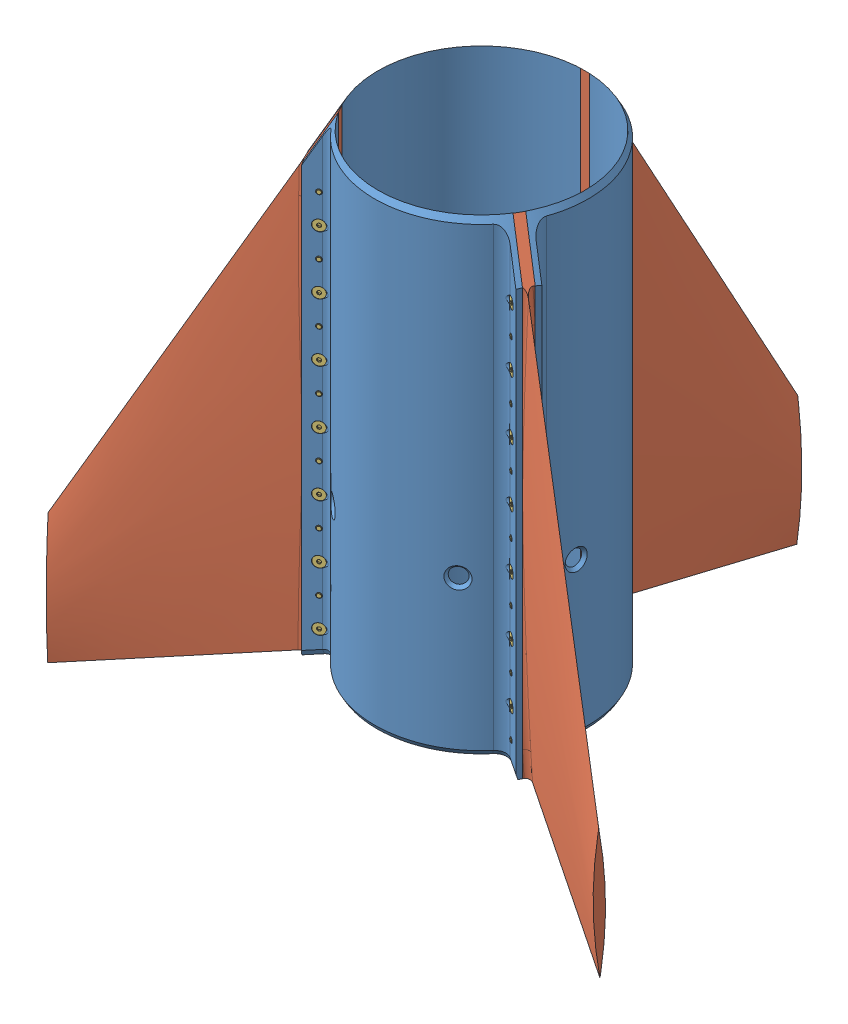
SolidWorks assembly Fin Can 3 Fin Asm, configuration Default. Lengths in mm.
Overall size (544.77 508.03 473.71).
50 component instances, 4 part files, 17 mates.
Components (placement in the parent):
- Binder Fin Can Section 3 - countersink 1-1: Binder Fin Can Section 3 - countersink 1 [Default] at origin size (110.04 463.46 186.39)
- BiconvexFin 3 Fin Fillet-4: BiconvexFin 3 Fin Fillet [Default] at (85.524 466.7433 54.8623) x (0 -1 0) z (0.866025 0 0.5) size (507.85 12.04 209.48)
- 91253A008_ 10-32 Black-Oxide Alloy Steel Hex Drive Flat Head Screw-1: 91253A008_ 10-32 Black-Oxide Alloy Steel Hex Drive Flat Head Screw [91253A008] at (0.3377 28.5749 -114.1971) x (0 0 1) z (-1 0 0) size (10.44 10.44 19.55)
- 91253A008_ 10-32 Black-Oxide Alloy Steel Hex Drive Flat Head Screw-28: 91253A008_ 10-32 Black-Oxide Alloy Steel Hex Drive Flat Head Screw [91253A008] at (-0.3377 57.15 -114.1971) x (0 0 1) z (1 0 0) size (10.44 10.44 19.55)
- 91253A008_ 10-32 Black-Oxide Alloy Steel Hex Drive Flat Head Screw-35: 91253A008_ 10-32 Black-Oxide Alloy Steel Hex Drive Flat Head Screw [91253A008] at (98.7287 28.5749 57.391) x (-0.866025 0 -0.5) z (0.5 0 -0.866025) size (10.44 10.44 19.55)
- 91253A008_ 10-32 Black-Oxide Alloy Steel Hex Drive Flat Head Screw-42: 91253A008_ 10-32 Black-Oxide Alloy Steel Hex Drive Flat Head Screw [91253A008] at (99.0664 57.15 56.8061) x (-0.801823 -0.377852 -0.462933) z (-0.5 0 0.866025) size (10.44 10.44 19.55)
- 91253A008_ 10-32 Black-Oxide Alloy Steel Hex Drive Flat Head Screw-49: 91253A008_ 10-32 Black-Oxide Alloy Steel Hex Drive Flat Head Screw [91253A008] at (-99.0664 28.5749 56.8061) x (-0.801823 -0.377852 0.462933) z (0.5 0 0.866025) size (10.44 10.44 19.55)
- 91253A008_ 10-32 Black-Oxide Alloy Steel Hex Drive Flat Head Screw-56: 91253A008_ 10-32 Black-Oxide Alloy Steel Hex Drive Flat Head Screw [91253A008] at (-98.7287 57.15 57.391) x (-0.801823 0.377852 0.462933) z (-0.5 0 -0.866025) size (10.44 10.44 19.55)
- Top Covers-2: Top Covers [Default] at (-230.5618 44.8886 -221.6505) x (0.414372 0.876196 -0.246124) z (0.563549 -0.034671 0.825355) (suppressed, hidden)
- Fin Bottom Wood-1: Fin Bottom Wood [Default] at (-200.4343 -0.6568 97.2389) x (0.854065 0.257277 -0.452086) z (0.461539 0.026031 0.886738) (suppressed, hidden)
- BiconvexFin 3 Fin Fillet-5: BiconvexFin 3 Fin Fillet [Default] at (4.7501 466.7433 -101.4971) x (0 -1 0) z (0 0 -1) size (507.85 12.04 209.48)
- BiconvexFin 3 Fin Fillet-6: BiconvexFin 3 Fin Fillet [Default] at (-90.2741 466.7433 46.6348) x (0 -1 0) z (-0.866025 0 0.5) size (507.85 12.04 209.48)
- Binder Fin Can Section 3 - countersink 1-2: Binder Fin Can Section 3 - countersink 1 [Default] x (-0.5 0 -0.866025) z (0.866025 0 -0.5) size (110.04 463.46 186.39)
- Binder Fin Can Section 3 - countersink 1-3: Binder Fin Can Section 3 - countersink 1 [Default] x (-0.5 0 0.866025) z (-0.866025 0 -0.5) size (110.04 463.46 186.39)
- 91253A008_ 10-32 Black-Oxide Alloy Steel Hex Drive Flat Head Screw-2: 91253A008_ 10-32 Black-Oxide Alloy Steel Hex Drive Flat Head Screw [91253A008] at (0.3377 85.7249 -114.1971) x (0 0 1) z (-1 0 0) size (10.44 10.44 19.55)
- 91253A008_ 10-32 Black-Oxide Alloy Steel Hex Drive Flat Head Screw-3: 91253A008_ 10-32 Black-Oxide Alloy Steel Hex Drive Flat Head Screw [91253A008] at (0.3377 142.8749 -114.1971) x (0 0 1) z (-1 0 0) size (10.44 10.44 19.55)
- 91253A008_ 10-32 Black-Oxide Alloy Steel Hex Drive Flat Head Screw-4: 91253A008_ 10-32 Black-Oxide Alloy Steel Hex Drive Flat Head Screw [91253A008] at (0.3377 200.0249 -114.1971) x (0 0 1) z (-1 0 0) size (10.44 10.44 19.55)
- 91253A008_ 10-32 Black-Oxide Alloy Steel Hex Drive Flat Head Screw-25: 91253A008_ 10-32 Black-Oxide Alloy Steel Hex Drive Flat Head Screw [91253A008] at (0.3377 257.1749 -114.1971) x (0 0 1) z (-1 0 0) size (10.44 10.44 19.55)
- 91253A008_ 10-32 Black-Oxide Alloy Steel Hex Drive Flat Head Screw-26: 91253A008_ 10-32 Black-Oxide Alloy Steel Hex Drive Flat Head Screw [91253A008] at (0.3377 314.3249 -114.1971) x (0 0 1) z (-1 0 0) size (10.44 10.44 19.55)
- 91253A008_ 10-32 Black-Oxide Alloy Steel Hex Drive Flat Head Screw-27: 91253A008_ 10-32 Black-Oxide Alloy Steel Hex Drive Flat Head Screw [91253A008] at (0.3377 371.4749 -114.1971) x (0 0 1) z (-1 0 0) size (10.44 10.44 19.55)
- 91253A008_ 10-32 Black-Oxide Alloy Steel Hex Drive Flat Head Screw-29: 91253A008_ 10-32 Black-Oxide Alloy Steel Hex Drive Flat Head Screw [91253A008] at (-0.3377 114.3 -114.1971) x (0 0 1) z (1 0 0) size (10.44 10.44 19.55)
- 91253A008_ 10-32 Black-Oxide Alloy Steel Hex Drive Flat Head Screw-30: 91253A008_ 10-32 Black-Oxide Alloy Steel Hex Drive Flat Head Screw [91253A008] at (-0.3377 171.45 -114.1971) x (0 0 1) z (1 0 0) size (10.44 10.44 19.55)
- 91253A008_ 10-32 Black-Oxide Alloy Steel Hex Drive Flat Head Screw-31: 91253A008_ 10-32 Black-Oxide Alloy Steel Hex Drive Flat Head Screw [91253A008] at (-0.3377 228.6 -114.1971) x (0 0 1) z (1 0 0) size (10.44 10.44 19.55)
- 91253A008_ 10-32 Black-Oxide Alloy Steel Hex Drive Flat Head Screw-32: 91253A008_ 10-32 Black-Oxide Alloy Steel Hex Drive Flat Head Screw [91253A008] at (-0.3377 285.75 -114.1971) x (0 0 1) z (1 0 0) size (10.44 10.44 19.55)
- 91253A008_ 10-32 Black-Oxide Alloy Steel Hex Drive Flat Head Screw-33: 91253A008_ 10-32 Black-Oxide Alloy Steel Hex Drive Flat Head Screw [91253A008] at (-0.3377 342.9 -114.1971) x (0 0 1) z (1 0 0) size (10.44 10.44 19.55)
- 91253A008_ 10-32 Black-Oxide Alloy Steel Hex Drive Flat Head Screw-34: 91253A008_ 10-32 Black-Oxide Alloy Steel Hex Drive Flat Head Screw [91253A008] at (-0.3377 400.05 -114.1971) x (0 0 1) z (1 0 0) size (10.44 10.44 19.55)
- 91253A008_ 10-32 Black-Oxide Alloy Steel Hex Drive Flat Head Screw-36: 91253A008_ 10-32 Black-Oxide Alloy Steel Hex Drive Flat Head Screw [91253A008] at (98.7287 85.7249 57.391) x (-0.866025 0 -0.5) z (0.5 0 -0.866025) size (10.44 10.44 19.55)
- 91253A008_ 10-32 Black-Oxide Alloy Steel Hex Drive Flat Head Screw-37: 91253A008_ 10-32 Black-Oxide Alloy Steel Hex Drive Flat Head Screw [91253A008] at (98.7287 142.8749 57.391) x (-0.866025 0 -0.5) z (0.5 0 -0.866025) size (10.44 10.44 19.55)
- 91253A008_ 10-32 Black-Oxide Alloy Steel Hex Drive Flat Head Screw-38: 91253A008_ 10-32 Black-Oxide Alloy Steel Hex Drive Flat Head Screw [91253A008] at (98.7287 200.0249 57.391) x (-0.866025 0 -0.5) z (0.5 0 -0.866025) size (10.44 10.44 19.55)
- 91253A008_ 10-32 Black-Oxide Alloy Steel Hex Drive Flat Head Screw-39: 91253A008_ 10-32 Black-Oxide Alloy Steel Hex Drive Flat Head Screw [91253A008] at (98.7287 257.1749 57.391) x (-0.866025 0 -0.5) z (0.5 0 -0.866025) size (10.44 10.44 19.55)
- 91253A008_ 10-32 Black-Oxide Alloy Steel Hex Drive Flat Head Screw-40: 91253A008_ 10-32 Black-Oxide Alloy Steel Hex Drive Flat Head Screw [91253A008] at (98.7287 314.3249 57.391) x (-0.866025 0 -0.5) z (0.5 0 -0.866025) size (10.44 10.44 19.55)
- 91253A008_ 10-32 Black-Oxide Alloy Steel Hex Drive Flat Head Screw-41: 91253A008_ 10-32 Black-Oxide Alloy Steel Hex Drive Flat Head Screw [91253A008] at (98.7287 371.4749 57.391) x (-0.866025 0 -0.5) z (0.5 0 -0.866025) size (10.44 10.44 19.55)
- 91253A008_ 10-32 Black-Oxide Alloy Steel Hex Drive Flat Head Screw-43: 91253A008_ 10-32 Black-Oxide Alloy Steel Hex Drive Flat Head Screw [91253A008] at (99.0664 114.3 56.8061) x (-0.801823 -0.377852 -0.462933) z (-0.5 0 0.866025) size (10.44 10.44 19.55)
- 91253A008_ 10-32 Black-Oxide Alloy Steel Hex Drive Flat Head Screw-44: 91253A008_ 10-32 Black-Oxide Alloy Steel Hex Drive Flat Head Screw [91253A008] at (99.0664 171.45 56.8061) x (-0.801823 -0.377852 -0.462933) z (-0.5 0 0.866025) size (10.44 10.44 19.55)
- 91253A008_ 10-32 Black-Oxide Alloy Steel Hex Drive Flat Head Screw-45: 91253A008_ 10-32 Black-Oxide Alloy Steel Hex Drive Flat Head Screw [91253A008] at (99.0664 228.6 56.8061) x (-0.801823 -0.377852 -0.462933) z (-0.5 0 0.866025) size (10.44 10.44 19.55)
- 91253A008_ 10-32 Black-Oxide Alloy Steel Hex Drive Flat Head Screw-46: 91253A008_ 10-32 Black-Oxide Alloy Steel Hex Drive Flat Head Screw [91253A008] at (99.0664 285.75 56.8061) x (-0.801823 -0.377852 -0.462933) z (-0.5 0 0.866025) size (10.44 10.44 19.55)
- 91253A008_ 10-32 Black-Oxide Alloy Steel Hex Drive Flat Head Screw-47: 91253A008_ 10-32 Black-Oxide Alloy Steel Hex Drive Flat Head Screw [91253A008] at (99.0664 342.9 56.8061) x (-0.801823 -0.377852 -0.462933) z (-0.5 0 0.866025) size (10.44 10.44 19.55)
- 91253A008_ 10-32 Black-Oxide Alloy Steel Hex Drive Flat Head Screw-48: 91253A008_ 10-32 Black-Oxide Alloy Steel Hex Drive Flat Head Screw [91253A008] at (99.0664 400.05 56.8061) x (-0.801823 -0.377852 -0.462933) z (-0.5 0 0.866025) size (10.44 10.44 19.55)
- 91253A008_ 10-32 Black-Oxide Alloy Steel Hex Drive Flat Head Screw-50: 91253A008_ 10-32 Black-Oxide Alloy Steel Hex Drive Flat Head Screw [91253A008] at (-99.0664 85.7249 56.8061) x (-0.801823 -0.377852 0.462933) z (0.5 0 0.866025) size (10.44 10.44 19.55)
- 91253A008_ 10-32 Black-Oxide Alloy Steel Hex Drive Flat Head Screw-51: 91253A008_ 10-32 Black-Oxide Alloy Steel Hex Drive Flat Head Screw [91253A008] at (-99.0664 142.8749 56.8061) x (-0.801823 -0.377852 0.462933) z (0.5 0 0.866025) size (10.44 10.44 19.55)
- 91253A008_ 10-32 Black-Oxide Alloy Steel Hex Drive Flat Head Screw-52: 91253A008_ 10-32 Black-Oxide Alloy Steel Hex Drive Flat Head Screw [91253A008] at (-99.0664 200.0249 56.8061) x (-0.801823 -0.377852 0.462933) z (0.5 0 0.866025) size (10.44 10.44 19.55)
- 91253A008_ 10-32 Black-Oxide Alloy Steel Hex Drive Flat Head Screw-53: 91253A008_ 10-32 Black-Oxide Alloy Steel Hex Drive Flat Head Screw [91253A008] at (-99.0664 257.1749 56.8061) x (-0.801823 -0.377852 0.462933) z (0.5 0 0.866025) size (10.44 10.44 19.55)
- 91253A008_ 10-32 Black-Oxide Alloy Steel Hex Drive Flat Head Screw-54: 91253A008_ 10-32 Black-Oxide Alloy Steel Hex Drive Flat Head Screw [91253A008] at (-99.0664 314.3249 56.8061) x (-0.801823 -0.377852 0.462933) z (0.5 0 0.866025) size (10.44 10.44 19.55)
- 91253A008_ 10-32 Black-Oxide Alloy Steel Hex Drive Flat Head Screw-55: 91253A008_ 10-32 Black-Oxide Alloy Steel Hex Drive Flat Head Screw [91253A008] at (-99.0664 371.4749 56.8061) x (-0.801823 -0.377852 0.462933) z (0.5 0 0.866025) size (10.44 10.44 19.55)
- 91253A008_ 10-32 Black-Oxide Alloy Steel Hex Drive Flat Head Screw-57: 91253A008_ 10-32 Black-Oxide Alloy Steel Hex Drive Flat Head Screw [91253A008] at (-98.7287 114.3 57.391) x (-0.801823 0.377852 0.462933) z (-0.5 0 -0.866025) size (10.44 10.44 19.55)
- 91253A008_ 10-32 Black-Oxide Alloy Steel Hex Drive Flat Head Screw-58: 91253A008_ 10-32 Black-Oxide Alloy Steel Hex Drive Flat Head Screw [91253A008] at (-98.7287 171.45 57.391) x (-0.801823 0.377852 0.462933) z (-0.5 0 -0.866025) size (10.44 10.44 19.55)
- 91253A008_ 10-32 Black-Oxide Alloy Steel Hex Drive Flat Head Screw-59: 91253A008_ 10-32 Black-Oxide Alloy Steel Hex Drive Flat Head Screw [91253A008] at (-98.7287 228.6 57.391) x (-0.801823 0.377852 0.462933) z (-0.5 0 -0.866025) size (10.44 10.44 19.55)
- 91253A008_ 10-32 Black-Oxide Alloy Steel Hex Drive Flat Head Screw-60: 91253A008_ 10-32 Black-Oxide Alloy Steel Hex Drive Flat Head Screw [91253A008] at (-98.7287 285.75 57.391) x (-0.801823 0.377852 0.462933) z (-0.5 0 -0.866025) size (10.44 10.44 19.55)
- 91253A008_ 10-32 Black-Oxide Alloy Steel Hex Drive Flat Head Screw-61: 91253A008_ 10-32 Black-Oxide Alloy Steel Hex Drive Flat Head Screw [91253A008] at (-98.7287 342.9 57.391) x (-0.801823 0.377852 0.462933) z (-0.5 0 -0.866025) size (10.44 10.44 19.55)
- 91253A008_ 10-32 Black-Oxide Alloy Steel Hex Drive Flat Head Screw-62: 91253A008_ 10-32 Black-Oxide Alloy Steel Hex Drive Flat Head Screw [91253A008] at (-98.7287 400.05 57.391) x (-0.801823 0.377852 0.462933) z (-0.5 0 -0.866025) size (10.44 10.44 19.55)
Mates (geometry in assembly coordinates):
- Coincident1: coincident anti-aligned: plane of Binder Fin Can Section 3 - countersink 1-1 through (90.185 508 46.7891) normal (-0.5 0 0.866025); plane of BiconvexFin 3 Fin Fillet-4 through (561.5246 496.7626 318.9171) normal (0.5 0 -0.866025)
- Coincident2: coincident aligned: plane of Binder Fin Can Section 3 - countersink 1-1 through (114.5633 508 55.3646) normal (0.866025 0 0.5); plane of BiconvexFin 3 Fin Fillet-4 through (107.4867 466.7433 67.6218) normal (0.866025 0 0.5)
- Concentric1: concentric aligned: cylinder of Binder Fin Can Section 3 - countersink 1-1 through (101.1836 28.5749 53.1391) axis (-0.5 0 0.866025) radius 2.4892; cylinder of BiconvexFin 3 Fin Fillet-4 through (96.6116 28.5749 61.058) axis (-0.5 0 0.866025) radius 2.4892
- Concentric2: concentric: cylinder of Binder Fin Can Section 3 - countersink 1-2 through (-4.572 28.5749 -114.1971) axis (1 0 0) radius 2.4892; circle of 92210A197_18-8 8-32 Stainless Steel Hex Drive Flat Head Screw-1
- Coincident3: coincident aligned: cone of Binder Fin Can Section 3 - countersink 1-2 through (-3.1182 28.5749 -114.1971) axis (1 0 0); cone of 92210A197_18-8 8-32 Stainless Steel Hex Drive Flat Head Screw-1 through (-5.5498 34.9247 -114.2076) axis (1 0 0)
- Concentric3: concentric aligned: cylinder of Binder Fin Can Section 3 - countersink 1-2 through (-4.572 28.5749 -114.1971) axis (1 0 0) radius 2.4892; circle of 92210A304_18-8 10-32 Stainless Steel Hex Drive Flat Head Screw-1
- Coincident4: coincident aligned: cone of Binder Fin Can Section 3 - countersink 1-2 through (-3.1182 28.5749 -114.1971) axis (1 0 0); cone of 91253A008_ 10-32 Black-Oxide Alloy Steel Hex Drive Flat Head Screw-1 through (-5.9615 28.5749 -114.1971) axis (1 0 0)
- Concentric4: concentric aligned: cylinder of Binder Fin Can Section 3 - countersink 1-1 through (4.572 57.15 -114.1971) axis (-1 0 0) radius 2.4892; circle of 92210A304_18-8 10-32 Stainless Steel Hex Drive Flat Head Screw-5
- Coincident5: coincident aligned: cone of Binder Fin Can Section 3 - countersink 1-1 through (3.1182 57.15 -114.1971) axis (-1 0 0); cone of 91253A008_ 10-32 Black-Oxide Alloy Steel Hex Drive Flat Head Screw-28 through (5.9615 57.15 -114.1971) axis (-1 0 0)
- Concentric5: concentric aligned: cylinder of Binder Fin Can Section 3 - countersink 1-1 through (101.1836 28.5749 53.1391) axis (-0.5 0 0.866025) radius 2.4892; circle of 92210A304_18-8 10-32 Stainless Steel Hex Drive Flat Head Screw-9
- Coincident6: coincident aligned: cone of Binder Fin Can Section 3 - countersink 1-1 through (100.4567 28.5749 54.3981) axis (-0.5 0 0.866025); cone of 91253A008_ 10-32 Black-Oxide Alloy Steel Hex Drive Flat Head Screw-35 through (101.8783 28.5749 51.9357) axis (-0.5 0 0.866025)
- Concentric6: concentric aligned: cylinder of Binder Fin Can Section 3 - countersink 1-3 through (96.6116 57.15 61.058) axis (0.5 0 -0.866025) radius 2.4892; circle of 92210A304_18-8 10-32 Stainless Steel Hex Drive Flat Head Screw-13
- Coincident7: coincident aligned: cone of Binder Fin Can Section 3 - countersink 1-3 through (97.3385 57.15 59.799) axis (0.5 0 -0.866025); cone of 91253A008_ 10-32 Black-Oxide Alloy Steel Hex Drive Flat Head Screw-42 through (95.9168 57.15 62.2613) axis (0.5 0 -0.866025)
- Concentric7: concentric aligned: cylinder of Binder Fin Can Section 3 - countersink 1-3 through (-96.6116 28.5749 61.058) axis (-0.5 0 -0.866025) radius 2.4892; circle of 92210A304_18-8 10-32 Stainless Steel Hex Drive Flat Head Screw-17
- Coincident8: coincident aligned: cone of Binder Fin Can Section 3 - countersink 1-3 through (-97.3385 28.5749 59.799) axis (-0.5 0 -0.866025); cone of 91253A008_ 10-32 Black-Oxide Alloy Steel Hex Drive Flat Head Screw-49 through (-95.9168 28.5749 62.2613) axis (-0.5 0 -0.866025)
- Concentric8: concentric aligned: cylinder of Binder Fin Can Section 3 - countersink 1-2 through (-101.1836 57.15 53.1391) axis (0.5 0 0.866025) radius 2.4892; circle of 92210A304_18-8 10-32 Stainless Steel Hex Drive Flat Head Screw-21
- Coincident12: coincident aligned: cone of Binder Fin Can Section 3 - countersink 1-2 through (-100.4567 57.15 54.3981) axis (0.5 0 0.866025); cone of 91253A008_ 10-32 Black-Oxide Alloy Steel Hex Drive Flat Head Screw-56 through (-101.8783 57.15 51.9357) axis (0.5 0 0.866025)
